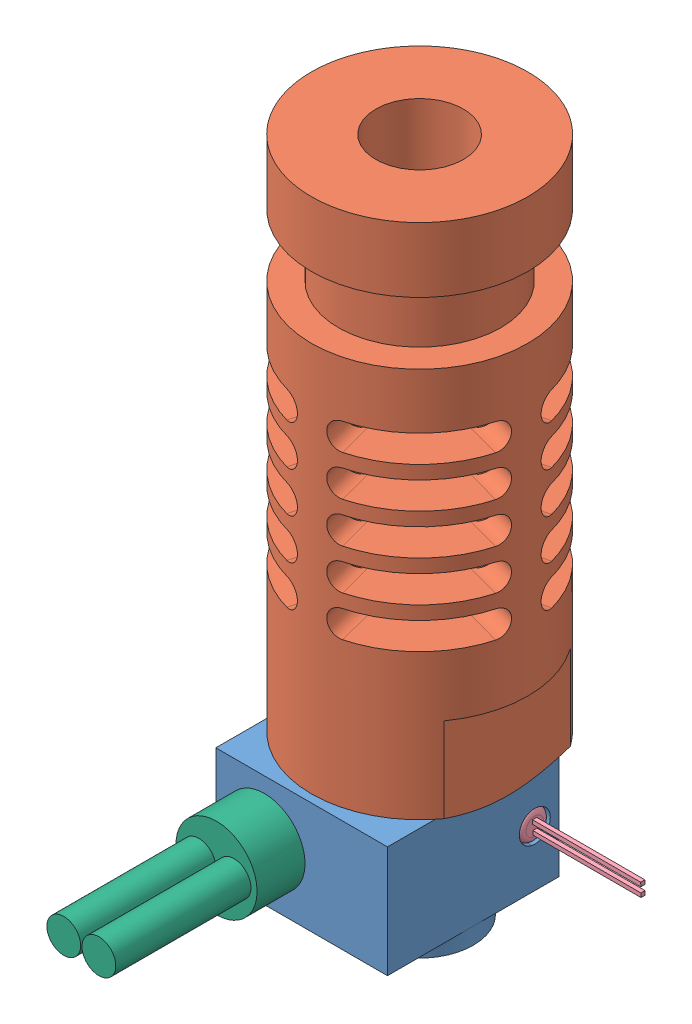
SolidWorks assembly Hot End Assembly, configuration Default. Lengths in mm.
Overall size (20.7 51.76 30).
6 component instances, 6 part files, 11 mates.
Components (placement in the parent):
- Nozzle-1: Nozzle [Default] at (45.787 -12.5943 19.4922) x (1 0 0) z (0 1 0) size (12.7 12.7 24)
- Nozzle Holder-1: Nozzle Holder [Default] at (65.9927 21.5658 13.9394) x (0.999992 0 0.004047) z (0 1 0) size (16 16 40)
- PTFE Tube-1: PTFE Tube [Default] at (36.0527 24.7939 9.6371) x (0.991805 0 0.127759) z (0 1 0) size (4 4 20)
- Thermistor-1: Thermistor [Default] at (10.2232 4.1275 5.9582) x (0 -0.028468 0.999595) z (-1 0 0) size (2.3 2.3 12.1)
- Hollow-Lock Socket-1: Hollow-Lock Socket [Default] at (32.1933 31.2801 -5.3865) x (0.710112 0 -0.704089) z (0 1 0) size (6.35 6.35 3.36)
- Ceramic Cartridge Heater-1: Ceramic Cartridge Heater [Default] at (5.2232 4.1275 20.4082) size (6 6 30)
Mates (geometry in assembly coordinates):
- Coincident1: coincident anti-aligned: plane of Nozzle-1 through (10.3532 0 10.5082) normal (0 -1 0); plane of assembly through (0 0 0) normal (0 1 0)
- Concentric1: concentric aligned: cylinder of Nozzle-1 through (10.3532 0 10.5082) axis (0 -1 0) radius 3.97; cylinder of Nozzle Holder-1 through (10.3532 24.476 10.5082) axis (0 -1 0) radius 3.97
- Distance1: distance = 0.5 mm anti-aligned: plane of Nozzle Holder-1 through (10.3734 8.755 5.5082) normal (0 -1 0); plane of Nozzle-1 through (10.3532 8.255 10.5082) normal (0 1 0)
- Concentric2: concentric aligned: cylinder of Nozzle-1 through (5.2232 4.1275 16.8582) axis (0 0 -1) radius 2.972; cylinder of Ceramic Cartridge Heater-1 through (5.2232 4.1275 20.4082) axis (0 0 -1) radius 3
- Distance2: distance = 3.75 mm aligned: plane of Ceramic Cartridge Heater-1 through (5.2232 4.1275 0.4082) normal (0 0 -1); plane of Nozzle-1 through (14.3232 8.255 4.1582) normal (0 0 -1)
- Concentric3: concentric anti-aligned: cylinder of Nozzle Holder-1 through (10.3532 48.758 10.5082) axis (0 -1 0) radius 3.24; cylinder of PTFE Tube-1 through (10.3532 41.003 10.5082) axis (0 1 0) radius 2
- Coincident4: coincident anti-aligned: plane of Nozzle-1 through (13.5932 21.003 10.5082) normal (0 1 0); plane of PTFE Tube-1 through (10.6087 21.003 8.5246) normal (0 -1 0)
- Coincident5: coincident anti-aligned: plane of PTFE Tube-1 through (10.4809 41.003 9.5164) normal (0 1 0); plane of Hollow-Lock Socket-1 through (8.5648 41.003 8.7045) normal (0 -1 0)
- Concentric5: concentric anti-aligned: cylinder of Nozzle Holder-1 through (10.3532 48.758 10.5082) axis (0 -1 0) radius 3.24; cylinder of Hollow-Lock Socket-1 through (10.3532 42.5905 10.5082) axis (0 1 0) radius 3.175
- Concentric7: concentric aligned: cylinder of Nozzle-1 through (1.6222 4.1275 5.9582) axis (1 0 0) radius 1.15; cylinder of Thermistor-1 through (10.2232 4.1275 5.9582) axis (1 0 0) radius 1.15
- Coincident6: coincident aligned: plane of Nozzle-1 through (14.3232 8.255 16.8582) normal (1 0 0); plane of Thermistor-1 through (14.3232 4.1275 5.9582) normal (1 0 0)
